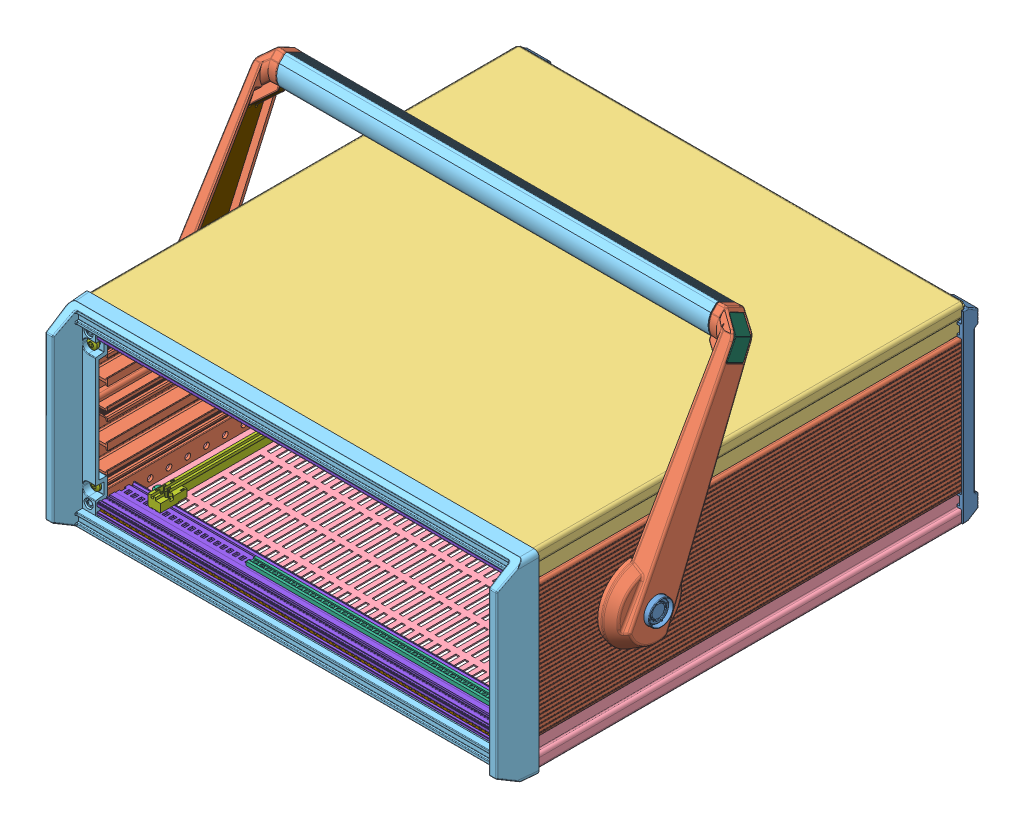
SolidWorks assembly Сборка3, configuration По умолчанию. Lengths in mm.
Overall size (403.98 263.48 385.3).
66 component instances, 27 part files, 93 mates.
Components (placement in the parent):
- RUECKFUSS-1: RUECKFUSS [По умолчанию] at (-181.5895 56.8307 -366.1601) x (-0.000005 0 1) z (-1 0 -0.000005) size (20.51 147.89 20.81)
- RUECKFUSS-2: RUECKFUSS [По умолчанию] at (181.1098 56.7192 -366.1792) x (0.000005 0 1) z (1 0 -0.000005) size (20.51 147.89 20.81)
- SEITENWAND-3HE-386T-1: SEITENWAND-3HE-386T [По умолчанию] at (164.6599 61.7249 -183.4869) x (0 1 0) z (0 0 -1) size (132.55 16.5 341.6)
- SEITENWAND-3HE-386T-2: SEITENWAND-3HE-386T [По умолчанию] at (-165.1396 51.8249 -183.4869) x (0 -1 0) z (0 0 -1) size (132.55 16.5 341.6)
- MANTEL-OB-----386T------63TE-1: MANTEL-OB-----386T------63TE [По умолчанию] at (-105.7766 133.7114 -281.6964) x (-1 0 0) z (0 -1 0) size (358.09 344.85 32)
- MANTEL-UN-----386T------63TE-1: MANTEL-UN-----386T------63TE [По умолчанию] at (105.2169 -19.4909 -281.6964) x (1 0 0) z (0 1 0) size (358.09 344.85 32)
- RAHMEN-3HE-63TE-1: RAHMEN-3HE-63TE [По умолчанию] at (0.0099 56.7749 -0.5026) size (363.7 155.5 35.01)
- 60224009-1: 60224009 [По умолчанию] at (-108.9949 51.9383 -35.4462) x (0.992 0 0.126242) z (-0.126242 0 0.992) size (16 11.2 16)
- 60224009-2: 60224009 [По умолчанию] at (-114.6549 51.9383 -332.8604) x (0.890513 0 -0.454958) z (0.454958 0 0.890513) size (16 11.2 16)
- 60224009-3: 60224009 [По умолчанию] at (148.3326 51.9382 11.108) x (-0.276623 0 0.960979) z (-0.960979 0 -0.276623) size (16 11.2 16)
- 60224009-4: 60224009 [По умолчанию] at (219.5313 51.9382 -307.4869) x (1 0 0) z (0 0 1) size (16 11.2 16)
- FLKOSHR-T-M-4-X16--1: FLKOSHR-T-M-4-X16- [По умолчанию] at (-168.8396 106.2499 2.3059) size (8.2 9.29 19.12)
- FLKOSHR-T-M-4-X16--2: FLKOSHR-T-M-4-X16- [По умолчанию] at (-168.8396 7.2999 0.1199) size (8.2 9.29 19.12)
- FLKOSHR-T-M-4-X16--3: FLKOSHR-T-M-4-X16- [По умолчанию] at (168.3599 106.2499 0.5037) size (8.2 9.29 19.12)
- FLKOSHR-T-M-4-X16--4: FLKOSHR-T-M-4-X16- [По умолчанию] at (168.3599 7.2999 1.0609) size (8.2 9.29 19.12)
- FLKOSHR-T-M-4-X16--5: FLKOSHR-T-M-4-X16- [По умолчанию] at (168.3599 7.2999 -344.7548) x (-1 0 0) z (0 0 -1) size (8.2 9.29 19.12)
- FLKOSHR-T-M-4-X16--6: FLKOSHR-T-M-4-X16- [По умолчанию] at (168.3599 106.2499 -328.1781) x (-1 0 0) z (0 0 -1) size (8.2 9.29 19.12)
- FLKOSHR-T-M-4-X16--7: FLKOSHR-T-M-4-X16- [По умолчанию] at (-168.8396 7.2999 -343.6567) x (-1 0 0) z (0 0 -1) size (8.2 9.29 19.12)
- FLKOSHR-T-M-4-X16--8: FLKOSHR-T-M-4-X16- [По умолчанию] at (-168.8396 106.2499 -343.7886) x (-1 0 0) z (0 0 -1) size (8.2 9.29 19.12)
- 34560763_3D-1: 34560763_3D [По умолчанию] at (-0.6422 113.5499 -311.9869) x (1 0 0) z (0 0 -1) size (325.12 9 30.5)
- 30845232_3D-1: 30845232_3D [По умолчанию] at (-0.7422 0.1253 -312.0869) x (-1 0 0) z (0 0 -1) size (324.92 5 1)
- 30845232_3D-2: 30845232_3D [По умолчанию] at (-0.5422 113.4246 -311.8869) x (1 0 0) z (0 0 -1) size (324.92 5 1)
- 34561363_3D-1: 34561363_3D [По умолчанию] at (-0.3922 113.4246 -311.7869) x (1 0 0) z (0 0 -1) size (324.62 5 2)
- 34561363_3D-2: 34561363_3D [По умолчанию] at (-0.8922 -8.8247 -311.9869) x (1 0 0) z (0 0 -1) size (324.62 5 2)
- 30849022-1: 30849022 [По умолчанию] at (-68.0617 34.3551 -334.6525) size (319.7 128.4 2.5)
- 24576-072-o-1: 24576-072-o [По умолчанию] at (0.0099 63.145 -78.2168) x (1 0 0) z (0 0.891933 -0.452168) size (403.98 60 209.99)
  - GRIFFSEITENTEIL-180-1: GRIFFSEITENTEIL-180 [По умолчанию] at (178.14 0 0) size (39.1 60 209.99)
    - LI--KO-SHR-M4x20-S-1: LI--KO-SHR-M4x20-S [По умолчанию] at (15.1 0 0) x (0 0 -1) z (1 0 0) size (8 8 23.08)
    - SCHEIBE-A43-SN27---1: SCHEIBE-A43-SN27-- [По умолчанию] at (15.1 0 0) x (0 0 -1) z (1 0 0) size (12 12 1)
    - STERNSCHEIBE-1: STERNSCHEIBE [По умолчанию] at origin size (2.5 38 38)
    - KAPPE-1: KAPPE [По умолчанию] at origin size (14.76 15.32 26.63)
    - ABDECKUNG-1: ABDECKUNG [По умолчанию] at origin size (14.07 31.26 14.09)
    - LAGER-1: LAGER [По умолчанию] at origin size (17.6 42.5 42.5)
    - SICHERHEITSLASCHE-180-1: SICHERHEITSLASCHE-180 [По умолчанию] at origin size (17.2 42 195.5)
    - KNOPF-1: KNOPF [По умолчанию] at origin size (19.32 19.8 19.8)
    - GRIFFSEITENTEIL-180-1: GRIFFSEITENTEIL-180 [По умолчанию] at origin size (29.21 60 209.99)
    - ZYL-KO-SHR-M5x16-S-1: ZYL-KO-SHR-M5x16-S [По умолчанию] at (0.75 0 169.25) x (0 0 -1) z (1 0 0) size (8.5 8.5 21)
    - FED-RING-DIN127-B5-1: FED-RING-DIN127-B5 [По умолчанию] at (0.77 0 169.25) x (0 0 -1) z (1 0 0) size (9.2 9.2 1.2)
  - GRIFFSEITENTEIL-180-2: GRIFFSEITENTEIL-180 [По умолчанию] at (-178.14 0 0) x (-1 0 0) z (0 0 1) size (39.1 60 209.99)
    - LI--KO-SHR-M4x20-S-1: LI--KO-SHR-M4x20-S [По умолчанию] at (15.1 0 0) x (0 0 -1) z (1 0 0) size (8 8 23.08)
    - SCHEIBE-A43-SN27---1: SCHEIBE-A43-SN27-- [По умолчанию] at (15.1 0 0) x (0 0 -1) z (1 0 0) size (12 12 1)
    - STERNSCHEIBE-1: STERNSCHEIBE [По умолчанию] at origin size (2.5 38 38)
    - KAPPE-1: KAPPE [По умолчанию] at origin size (14.76 15.32 26.63)
    - ABDECKUNG-1: ABDECKUNG [По умолчанию] at origin size (14.07 31.26 14.09)
    - LAGER-1: LAGER [По умолчанию] at origin size (17.6 42.5 42.5)
    - SICHERHEITSLASCHE-180-1: SICHERHEITSLASCHE-180 [По умолчанию] at origin size (17.2 42 195.5)
    - KNOPF-1: KNOPF [По умолчанию] at origin size (19.32 19.8 19.8)
    - GRIFFSEITENTEIL-180-1: GRIFFSEITENTEIL-180 [По умолчанию] at origin size (29.21 60 209.99)
    - ZYL-KO-SHR-M5x16-S-1: ZYL-KO-SHR-M5x16-S [По умолчанию] at (0.75 0 169.25) x (0 0 -1) z (1 0 0) size (8.5 8.5 21)
    - FED-RING-DIN127-B5-1: FED-RING-DIN127-B5 [По умолчанию] at (0.77 0 169.25) x (0 0 -1) z (1 0 0) size (9.2 9.2 1.2)
  - GR-STANGE-63TE-----1: GR-STANGE-63TE---- [По умолчанию] at origin size (344.98 20.84 21.8)
- 34560763_3D-4: 34560763_3D [По умолчанию] at (-0.6422 -0.0001 -11.9868) size (325.12 9 30.5)
- 30845232_3D-3: 30845232_3D [По умолчанию] at (-0.5422 122.6246 -11.8868) size (324.92 5 1)
- 30845232_3D-4: 30845232_3D [По умолчанию] at (-0.7422 0.1253 -12.0868) size (324.92 5 1)
- 34561363_3D-3: 34561363_3D [По умолчанию] at (-0.3922 122.6246 -11.9868) size (324.62 5 2)
- 34561363_3D-4: 34561363_3D [По умолчанию] at (-0.8922 0.1253 -12.1868) size (324.62 5 2)
- 34560763_3D-5: 34560763_3D [По умолчанию] at (-0.6422 -0.0001 -311.9869) x (-1 0 0) z (0 0 -1) size (325.12 9 30.5)
- 34560763_3D-6: 34560763_3D [По умолчанию] at (-0.6422 113.5499 -11.9868) x (-1 0 0) z (0 0 1) size (325.12 9 30.5)
- 60817-118-o-1: 60817-118-o [По умолчанию] at (45.1668 -17.2501 -7.5545) x (-1 0 0) z (0 1 0) size (210.2 7.8 3.8)
- 60817-118-o-2: 60817-118-o [По умолчанию] at (45.1668 -17.2501 -316.589) x (1 0 0) z (0 1 0) size (210.2 7.8 3.8)
- 24560375_s-1: 24560375_s [По умолчанию] at (-137.8022 0.4462 -11.4868) size (10.08 16 258)
- 34561342-1: 34561342 [По умолчанию] at (52.9478 -16.5501 -16.4618) x (1 0 0) z (0 1 0) size (217.94 5 2)
- 34561342-2: 34561342 [По умолчанию] at (52.9478 11.5499 -307.5119) x (1 0 0) z (0 -1 0) size (217.94 5 2)
- 24560375_s-2: 24560375_s [По умолчанию] at (-137.8022 118.4446 -266.4868) x (1 0 0) z (0 0 -1) size (10.08 16 258)
- 34560563_3D-1: 34560563_3D [По умолчанию] at (-0.6422 -0.0001 -266.9868) size (325.12 9 27.5)
- 34560563_3D-2: 34560563_3D [По умолчанию] at (-0.6422 113.5499 -266.9868) x (-1 0 0) z (0 0 1) size (325.12 9 27.5)
Mates (geometry in assembly coordinates):
- Концентричный1: concentric anti-aligned: cylinder of MANTEL-UN-----386T------63TE-1 through (-164.3199 -19.4909 -307.4869) axis (0 1 0) radius 3.5; circle of 60224009-2
- Концентричный2: concentric anti-aligned: cylinder of MANTEL-UN-----386T------63TE-1 through (-164.3199 -19.4909 -42.4869) axis (0 1 0) radius 3.5; circle of 60224009-1
- Концентричный3: concentric anti-aligned: cylinder of MANTEL-UN-----386T------63TE-1 through (163.7601 -19.4909 -42.4869) axis (0 1 0) radius 3.5; circle of 60224009-3
- Концентричный4: concentric anti-aligned: cylinder of MANTEL-UN-----386T------63TE-1 through (163.7601 -19.4909 -307.4869) axis (0 1 0) radius 3.5; circle of 60224009-4
- Совпадение1: coincident aligned: plane of 60224009-2 through (-167.7239 -15.029 -308.5888) normal (0 1 0); plane of 60224009-4 through (161.2301 -15.0291 -310.0169) normal (0 1 0)
- Совпадение2: coincident aligned: plane of 60224009-1 through (-166.5102 -15.029 -45.316) normal (0 1 0); plane of 60224009-2 through (-167.7239 -15.029 -308.5888) normal (0 1 0)
- Совпадение3: coincident aligned: plane of 60224009-1 through (-166.5102 -15.029 -45.316) normal (0 1 0); plane of 60224009-3 through (166.8913 -15.0291 -44.2183) normal (0 1 0)
- Совпадение4: coincident anti-aligned: plane of SEITENWAND-3HE-386T-1 through (174.2601 3.7999 -0.4869) normal (1 0 0); plane of MANTEL-UN-----386T------63TE-1 through (174.2601 -7.7909 -343.5869) normal (-1 0 0)
- Расстояние1: distance = 0 mm: plane of SEITENWAND-3HE-386T-1 through (179.5726 -11.2569 -0.4869) normal (0 0 1); point of MANTEL-UN-----386T------63TE-1
- Перпендикулярность1: perpendicular: plane of SEITENWAND-3HE-386T-1 through (175.3599 15.8249 -0.4869) normal (0 1 0); plane of MANTEL-UN-----386T------63TE-1 through (-197.2239 5.1841 -0.4869) normal (0 0 1)
- Совпадение6: coincident anti-aligned: plane of SEITENWAND-3HE-386T-1 through (174.2601 109.7499 -0.4869) normal (1 0 0); plane of MANTEL-OB-----386T------63TE-1 through (174.2601 122.0114 -0.4869) normal (-1 0 0)
- Расстояние2: distance = 0 mm: plane of SEITENWAND-3HE-386T-1 through (179.5726 -11.2569 -0.4869) normal (0 0 1); point of MANTEL-OB-----386T------63TE-1
- Перпендикулярность2: perpendicular: plane of SEITENWAND-3HE-386T-1 through (164.0599 79.9999 -0.4869) normal (0 1 0); plane of MANTEL-OB-----386T------63TE-1 through (196.6641 109.0364 -0.4869) normal (0 0 1)
- Концентричный5: concentric anti-aligned: circle of SEITENWAND-3HE-386T-1; circle of FLKOSHR-T-M-4-X16--6
- Концентричный6: concentric aligned: circle of SEITENWAND-3HE-386T-1; circle of FLKOSHR-T-M-4-X16--5
- Концентричный7: concentric anti-aligned: circle of SEITENWAND-3HE-386T-2; circle of FLKOSHR-T-M-4-X16--7
- Концентричный8: concentric aligned: circle of SEITENWAND-3HE-386T-2; circle of FLKOSHR-T-M-4-X16--8
- Совпадение8: coincident: cone of RUECKFUSS-2 through (168.3599 106.2499 -350.291) axis (0 0 1); circle of FLKOSHR-T-M-4-X16--6
- Перпендикулярность3: perpendicular: plane of RUECKFUSS-2 through (181.1099 123.775 -352.2909) normal (0 -0.999391 -0.034899); plane of SEITENWAND-3HE-386T-1 through (177.0599 80.8391 -0.4869) normal (-1 0 0)
- Концентричный9: concentric aligned: cone of RUECKFUSS-1 through (-168.8396 106.2499 -350.2719) axis (0 0 1); circle of FLKOSHR-T-M-4-X16--8
- Перпендикулярность4: perpendicular: plane of RUECKFUSS-1 through (-181.5896 123.775 -352.2718) normal (0 -0.999391 -0.034899); plane of SEITENWAND-3HE-386T-2 through (-177.5396 80.8391 -0.4869) normal (1 0 0)
- Концентричный10: concentric aligned: circle of SEITENWAND-3HE-386T-2; circle of FLKOSHR-T-M-4-X16--1
- Концентричный11: concentric anti-aligned: circle of SEITENWAND-3HE-386T-2; circle of FLKOSHR-T-M-4-X16--2
- Концентричный12: concentric anti-aligned: circle of SEITENWAND-3HE-386T-1; circle of FLKOSHR-T-M-4-X16--3
- Концентричный13: concentric aligned: circle of SEITENWAND-3HE-386T-1; circle of FLKOSHR-T-M-4-X16--4
- Концентричный14: concentric anti-aligned: cone of RAHMEN-3HE-63TE-1 through (168.3599 7.2999 2.4974) axis (0 0 1); circle of FLKOSHR-T-M-4-X16--4
- Перпендикулярность5: perpendicular: plane of SEITENWAND-3HE-386T-1 through (162.5599 108.4499 -0.4869) normal (-1 0 0); plane of RAHMEN-3HE-63TE-1 through (181.9174 129.2249 15.5974) normal (0 -1 0)
- Совпадение9: coincident aligned: plane of SEITENWAND-3HE-386T-1 through (162.5599 123.0499 -0.4869) normal (0 1 0); plane of SEITENWAND-3HE-386T-2 through (-163.0397 123.0499 -0.4869) normal (0 1 0)
- Совпадение10: coincident aligned: plane of SEITENWAND-3HE-386T-1 through (179.5726 -11.2569 -0.4869) normal (0 0 1); plane of SEITENWAND-3HE-386T-2 through (-180.0524 124.8067 -0.4869) normal (0 0 1)
- Расстояние3: distance = 349 mm: plane of SEITENWAND-3HE-386T-2 through (-174.7399 109.7499 -0.4869) normal (-1 0 0); point of SEITENWAND-3HE-386T-1
- Совпадение11: coincident anti-aligned: plane of 34560763_3D-1 through (161.9178 116.2496 -324.8369) normal (0 0 -1); plane of 34561363_3D-1 through (-163.6792 114.6746 -324.8369) normal (0 0 1)
- Совпадение12: coincident anti-aligned: plane of 34560763_3D-1 through (161.9178 115.3996 -324.8369) normal (0 1 0); plane of 34561363_3D-1 through (-163.5522 115.3996 -327.4369) normal (0 -1 0)
- Совпадение13: coincident aligned: plane of 34560763_3D-1 through (161.9178 122.1749 -332.9994) normal (1 0 0); plane of 34561363_3D-1 through (161.9178 115.8996 -324.3369) normal (1 0 0)
- Совпадение14: coincident anti-aligned: plane of 34560763_3D-1 through (161.9178 116.2496 -329.0369) normal (0 0 -1); plane of 30845232_3D-2 through (-163.8292 114.6746 -329.0369) normal (0 0 1)
- Совпадение15: coincident aligned: plane of 34560763_3D-1 through (161.9178 122.1749 -332.9994) normal (1 0 0); plane of 30845232_3D-2 through (161.9178 115.8996 -328.0369) normal (1 0 0)
- Совпадение16: coincident anti-aligned: plane of 34560763_3D-1 through (161.9178 115.3996 -329.0369) normal (0 1 0); plane of 30845232_3D-2 through (-163.7022 115.3996 -330.6369) normal (0 -1 0)
- Концентричный15: concentric aligned: cylinder of SEITENWAND-3HE-386T-1 through (164.5599 117.7499 -304.4869) axis (-1 0 0) radius 2.3; circle of 34560763_3D-1
- Концентричный17: concentric aligned: cylinder of SEITENWAND-3HE-386T-1 through (164.5599 117.7499 -319.4869) axis (-1 0 0) radius 2.3; circle of 34560763_3D-1
- Ширина1: width anti-aligned: plane of 34560763_3D-1 through (161.9178 122.1749 -332.9994) normal (1 0 0); plane of 34560763_3D-1 through (-163.2022 112.7249 -300.9744) normal (-1 0 0); plane of 30849022-1 through (-160.4922 -7.3754 -334.6525) normal (-1 0 0); plane of 30849022-1 through (159.2078 121.0246 -334.6525) normal (1 0 0)
- Ширина2: width anti-aligned: plane of 34560763_3D-1 through (161.9178 119.7996 -329.0369) normal (0 -1 0); plane of 34560763_3D-1 through (161.9178 116.2496 -327.0369) normal (0 1 0); plane of 30849022-1 through (149.3124 116.3746 -332.1525) normal (0 1 0); plane of 30849022-1 through (154.2032 119.6746 -332.1525) normal (0 -1 0)
- Расстояние4: distance = 0 mm: plane of RUECKFUSS-2 through (181.1099 122.775 -352.2909) normal (-0.000005 0 -1); point of RUECKFUSS-1
- Ширина3: width aligned: plane of ? through (198.8445 48.5544 -53.1146) normal (-0.9994 -0.030898 0.015664); plane of ? through (-198.8246 34.273 -81.2855) normal (0.9994 -0.030898 0.015664); plane of RAHMEN-3HE-63TE-1 through (-181.9168 134.6249 -2.2589) normal (-0.999048 0 0.043619); plane of RAHMEN-3HE-63TE-1 through (181.9366 134.6249 -2.2589) normal (0.999048 0 0.043619)
- Расстояние5: distance = 80 mm: plane of SEITENWAND-3HE-386T-1 through (179.5726 -11.2569 -0.4869) normal (0 0 1); point of 24576-072-o-1/GRIFFSEITENTEIL-180-1/LAGER-1
- Расстояние6: distance = 1 mm: plane of SEITENWAND-3HE-386T-2 through (-164.5397 59.8749 -0.4869) normal (0 1 0); point of 24576-072-o-1/GRIFFSEITENTEIL-180-2/LAGER-1
- Концентричный21: concentric aligned: cylinder of SEITENWAND-3HE-386T-2 through (-165.0396 -4.2001 -19.4869) axis (1 0 0) radius 2.3; circle of 34560763_3D-4
- Концентричный22: concentric anti-aligned: cylinder of SEITENWAND-3HE-386T-2 through (-165.0396 -4.2001 -4.4869) axis (1 0 0) radius 2.3; circle of 34560763_3D-4
- Совпадение31: coincident aligned: plane of 34560763_3D-4 through (-163.2022 0.8249 -22.9993) normal (-1 0 0); plane of 34561363_3D-4 through (-163.2022 -6.3497 0.3632) normal (-1 0 0)
- Совпадение32: coincident aligned: plane of 34560763_3D-4 through (-163.2022 0.8249 -22.9993) normal (-1 0 0); plane of 30845232_3D-4 through (-163.2022 -6.3497 4.0632) normal (-1 0 0)
- Совпадение33: coincident anti-aligned: plane of 34560763_3D-4 through (161.9178 -1.8497 0.8632) normal (0 -1 0); plane of 34561363_3D-4 through (-164.0522 -1.8497 3.4632) normal (0 1 0)
- Совпадение34: coincident anti-aligned: plane of 34560763_3D-4 through (161.9178 -1.8497 5.0632) normal (0 -1 0); plane of 30845232_3D-4 through (-163.9022 -1.8497 6.6632) normal (0 1 0)
- Совпадение35: coincident anti-aligned: plane of 34560763_3D-4 through (161.9178 -2.6998 0.8632) normal (0 0 1); plane of 34561363_3D-4 through (-164.1792 -1.1247 0.8632) normal (0 0 -1)
- Совпадение36: coincident anti-aligned: plane of 34560763_3D-4 through (161.9178 -2.6998 5.0632) normal (0 0 1); plane of 30845232_3D-4 through (-164.0292 -1.1247 5.0632) normal (0 0 -1)
- Концентричный23: concentric anti-aligned: cylinder of SEITENWAND-3HE-386T-1 through (164.5599 -4.2001 -319.4869) axis (-1 0 0) radius 2.3; circle of 34560763_3D-5
- Концентричный24: concentric anti-aligned: cylinder of SEITENWAND-3HE-386T-1 through (164.5599 -4.2001 -304.4869) axis (-1 0 0) radius 2.3; circle of 34560763_3D-5
- Совпадение37: coincident aligned: plane of 34560763_3D-1 through (-163.2022 112.7249 -300.9744) normal (-1 0 0); plane of 34560763_3D-5 through (-163.2022 -8.6251 -332.9994) normal (-1 0 0)
- Совпадение38: coincident anti-aligned: plane of 34561363_3D-2 through (162.3948 -1.1247 -327.0369) normal (0 0 -1); plane of 34560763_3D-5 through (-163.2022 -1.8497 -327.0369) normal (0 0 1)
- Совпадение39: coincident anti-aligned: plane of 34561363_3D-2 through (162.2678 -1.8497 -327.6369) normal (0 1 0); plane of 34560763_3D-5 through (-163.2022 -1.8497 -324.8369) normal (0 -1 0)
- Совпадение40: coincident aligned: plane of 34561363_3D-2 through (-163.2022 -2.3497 -324.5369) normal (-1 0 0); plane of 34560763_3D-5 through (-163.2022 -8.6251 -332.9994) normal (-1 0 0)
- Совпадение42: coincident anti-aligned: plane of 30845232_3D-1 through (-164.0292 -7.5747 -330.2369) normal (0 0 -1); plane of 34560763_3D-5 through (-163.2022 -1.8497 -330.2369) normal (0 0 1)
- Совпадение43: coincident anti-aligned: plane of 30845232_3D-1 through (162.4178 -1.8497 -330.8369) normal (0 1 0); plane of 34560763_3D-5 through (-163.2022 -1.8497 -329.0369) normal (0 -1 0)
- Совпадение44: coincident aligned: plane of 30845232_3D-1 through (-163.2022 -2.3497 -328.2369) normal (-1 0 0); plane of 34560763_3D-5 through (-163.2022 -8.6251 -332.9994) normal (-1 0 0)
- Концентричный25: concentric aligned: cylinder of SEITENWAND-3HE-386T-1 through (164.5599 117.7499 -19.4869) axis (-1 0 0) radius 2.3; circle of 34560763_3D-6
- Концентричный26: concentric aligned: cylinder of SEITENWAND-3HE-386T-1 through (164.5599 117.7499 -4.4869) axis (-1 0 0) radius 2.3; circle of 34560763_3D-6
- Совпадение45: coincident anti-aligned: plane of 34561363_3D-3 through (162.8948 114.9246 3.0632) normal (0 0 1); plane of 34560763_3D-6 through (-163.2022 119.7996 3.0632) normal (0 0 -1)
- Совпадение46: coincident anti-aligned: plane of 34561363_3D-3 through (-163.5522 120.6496 3.6632) normal (0 1 0); plane of 34560763_3D-6 through (-163.2022 120.6496 3.0632) normal (0 -1 0)
- Совпадение47: coincident aligned: plane of 34561363_3D-3 through (161.9178 120.1496 0.5632) normal (1 0 0); plane of 34560763_3D-6 through (161.9178 112.7249 -22.9993) normal (1 0 0)
- Совпадение48: coincident anti-aligned: plane of 30845232_3D-3 through (-163.7022 120.6496 6.8632) normal (0 1 0); plane of 34560763_3D-6 through (-163.2022 120.6496 6.2632) normal (0 -1 0)
- Совпадение49: coincident anti-aligned: plane of 30845232_3D-3 through (162.7448 114.9246 6.2632) normal (0 0 1); plane of 34560763_3D-6 through (-163.2022 119.7996 6.2632) normal (0 0 -1)
- Совпадение50: coincident aligned: plane of 30845232_3D-3 through (161.9178 120.1496 4.2632) normal (1 0 0); plane of 34560763_3D-6 through (161.9178 112.7249 -22.9993) normal (1 0 0)
- Совпадение51: coincident aligned: plane of 34560763_3D-4 through (161.9178 -8.6251 9.0257) normal (1 0 0); plane of 34560763_3D-6 through (161.9178 112.7249 -22.9993) normal (1 0 0)
- Совпадение52: coincident anti-aligned: plane of 34560763_3D-4 through (161.9178 -0.0001 -6.0368) normal (0 1 0); plane of 60817-118-o-1 through (150.2668 -0.0001 -15.9295) normal (0 -1 0)
- Расстояние7: distance = 10.151 mm: plane of 34560763_3D-4 through (160.4178 -0.0001 -9.9868) normal (1 0 0); point of 60817-118-o-1
- Параллельность2: parallel aligned: plane of 34560763_3D-4 through (160.4178 -0.0001 -9.9868) normal (1 0 0); plane of 60817-118-o-1 through (150.2668 3.1749 -7.8345) normal (1 0 0)
- Совпадение54: coincident anti-aligned: plane of 34560763_3D-5 through (-163.2022 -0.0001 -317.9369) normal (0 1 0); plane of 60817-118-o-2 through (-59.9332 -0.0001 -308.214) normal (0 -1 0)
- Параллельность3: parallel aligned: plane of 34560763_3D-5 through (161.9178 0.8249 -300.9744) normal (1 0 0); plane of 60817-118-o-2 through (150.2668 2.9999 -307.214) normal (1 0 0)
- Расстояние8: distance = 10.151 mm: plane of 34560763_3D-5 through (160.4178 -0.0001 -309.9869) normal (1 0 0); point of 60817-118-o-2
- Совпадение55: coincident aligned: plane of 34560763_3D-1 through (161.9178 122.1749 -332.9994) normal (1 0 0); plane of 34560763_3D-6 through (161.9178 112.7249 -22.9993) normal (1 0 0)
- Совпадение60: coincident anti-aligned: plane of 34560763_3D-4 through (161.9178 -1.5001 -15.9368) normal (0 -1 0); plane of 34561342-1 through (162.7948 -1.5001 -8.5618) normal (0 1 0)
- Совпадение61: coincident aligned: plane of 34560763_3D-4 through (161.9178 -8.6251 9.0257) normal (1 0 0); plane of 34561342-1 through (161.9178 -4.0001 -13.9868) normal (1 0 0)
- Ширина9: width anti-aligned: plane of 34560763_3D-4 through (161.9178 -2.3001 -7.2368) normal (0 0 -1); plane of 34560763_3D-4 through (161.9178 -7.6001 -16.7368) normal (0 0 1); plane of 34561342-1 through (162.6678 -0.7001 -9.4868) normal (0 0 1); plane of 34561342-1 through (-56.4722 -0.7001 -14.4868) normal (0 0 -1)
- Совпадение62: coincident anti-aligned: plane of 34560763_3D-5 through (-163.2022 -1.5001 -308.0369) normal (0 -1 0); plane of 34561342-2 through (-56.5992 -1.5001 -308.5619) normal (0 1 0)
- Совпадение63: coincident aligned: plane of 34560763_3D-5 through (161.9178 0.8249 -300.9744) normal (1 0 0); plane of 34561342-2 through (161.9178 -1.0001 -309.9869) normal (1 0 0)
- Ширина10: width aligned: plane of 34560763_3D-5 through (-163.2022 -7.6001 -307.2369) normal (0 0 -1); plane of 34560763_3D-5 through (-163.2022 -2.3001 -316.7369) normal (0 0 1); plane of 34561342-2 through (162.6678 -4.3001 -314.4869) normal (0 0 -1); plane of 34561342-2 through (-56.4722 -4.3001 -309.4869) normal (0 0 1)
- Ширина11: width anti-aligned: plane of 24560375_s-1 through (-140.0472 -1.102 -8.9868) normal (-1 0 0); plane of 24560375_s-1 through (-130.4772 -1.8417 -8.9868) normal (1 0 0); plane of 34560763_3D-4 through (-139.3022 -0.0001 -9.9868) normal (1 0 0); plane of 34560763_3D-4 through (-131.2222 -0.0001 -13.9868) normal (-1 0 0)
- Совпадение64: coincident anti-aligned: plane of 34560763_3D-4 through (-136.3022 -0.0001 -9.9868) normal (0 0 -1); plane of 24560375_s-1 through (-140.3022 9.998 -9.9868) normal (0 0 1)
- Совпадение65: coincident anti-aligned: plane of 34560763_3D-6 through (-144.3822 113.5499 -9.9868) normal (0 0 -1); plane of 24560375_s-2 through (-140.3022 108.8929 -9.9868) normal (0 0 1)
- Ширина12: width anti-aligned: plane of 24560375_s-2 through (-140.0472 119.9929 -8.9868) normal (-1 0 0); plane of 24560375_s-2 through (-130.4772 120.7326 -8.9868) normal (1 0 0); plane of 34560763_3D-6 through (-139.3022 113.5499 -13.9868) normal (1 0 0); plane of 34560763_3D-6 through (-131.2222 113.5499 -9.9868) normal (-1 0 0)
- Совпадение66: coincident aligned: plane of 34560563_3D-1 through (161.9178 -0.0001 -266.9868) normal (1 0 0); plane of 34560763_3D-6 through (161.9178 112.7249 -22.9993) normal (1 0 0)
- Совпадение67: coincident aligned: plane of 34560763_3D-6 through (161.9178 112.7249 -22.9993) normal (1 0 0); plane of 34560563_3D-2 through (161.9178 113.5499 -266.9868) normal (1 0 0)
- Концентричный27: concentric anti-aligned: cylinder of SEITENWAND-3HE-386T-1 through (164.5599 -4.2001 -274.4869) axis (-1 0 0) radius 2.3; circle of 34560563_3D-1
- Концентричный28: concentric anti-aligned: cylinder of SEITENWAND-3HE-386T-1 through (164.5599 -4.2001 -259.4869) axis (-1 0 0) radius 2.3; circle of 34560563_3D-1
- Концентричный29: concentric aligned: cylinder of SEITENWAND-3HE-386T-1 through (164.5599 117.7499 -274.4869) axis (-1 0 0) radius 2.3; circle of 34560563_3D-2
- Концентричный30: concentric aligned: cylinder of SEITENWAND-3HE-386T-1 through (164.5599 117.7499 -259.4869) axis (-1 0 0) radius 2.3; circle of 34560563_3D-2
